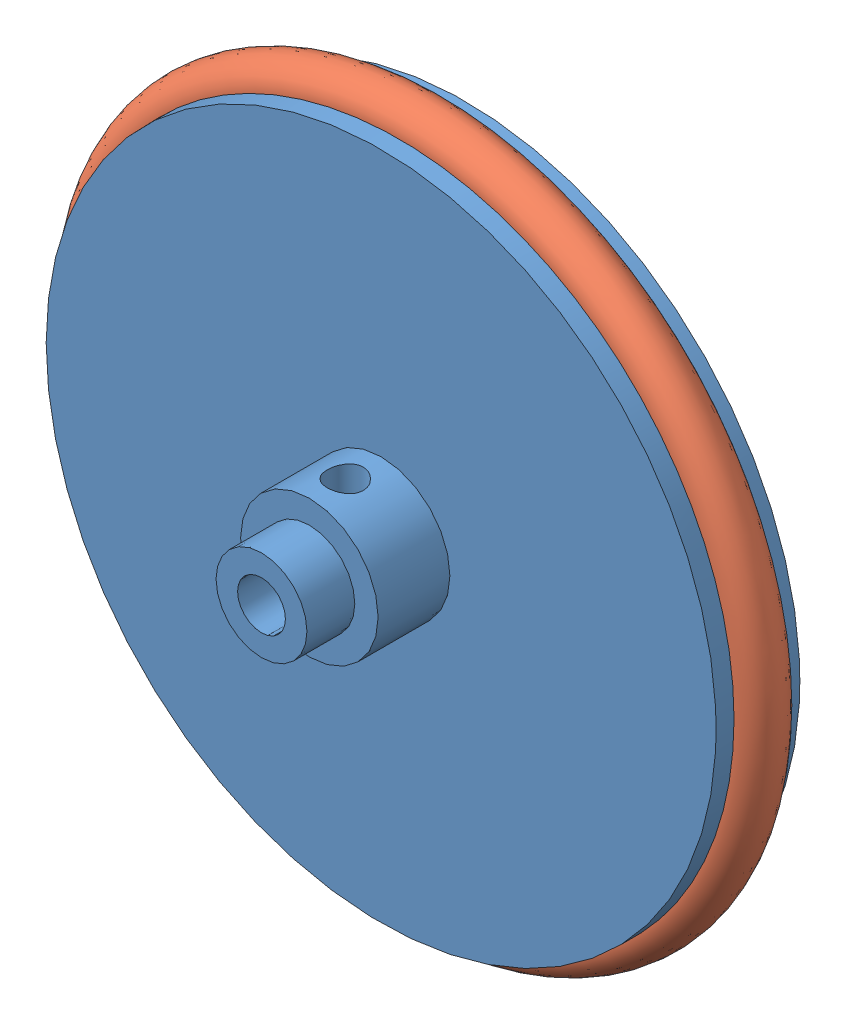
SolidWorks assembly Assemblage Roue Codeuse, configuration Défaut. Lengths in mm.
Overall size (60 60 17).
2 component instances, 2 part files, 2 mates.
Components (placement in the parent):
- Roue folle D56 BRS-1: Roue folle D56 BRS [Défaut] at (44.4504 10.553 -33.3566) size (56 56 17)
- Joint Torique D52 T4 BRS-1: Joint Torique D52 T4 BRS [Défaut] at (44.4504 10.553 -29.8566) size (60 60 4)
Mates (geometry in assembly coordinates):
- Coïncidente1: coincident aligned: circle of Roue folle D46 BRS-1; circle of Joint Torique D52 T4 BRS-1
- Coïncidente2: coincident aligned: circle of Roue folle D46 BRS-1; circle of Joint Torique D52 T4 BRS-1
